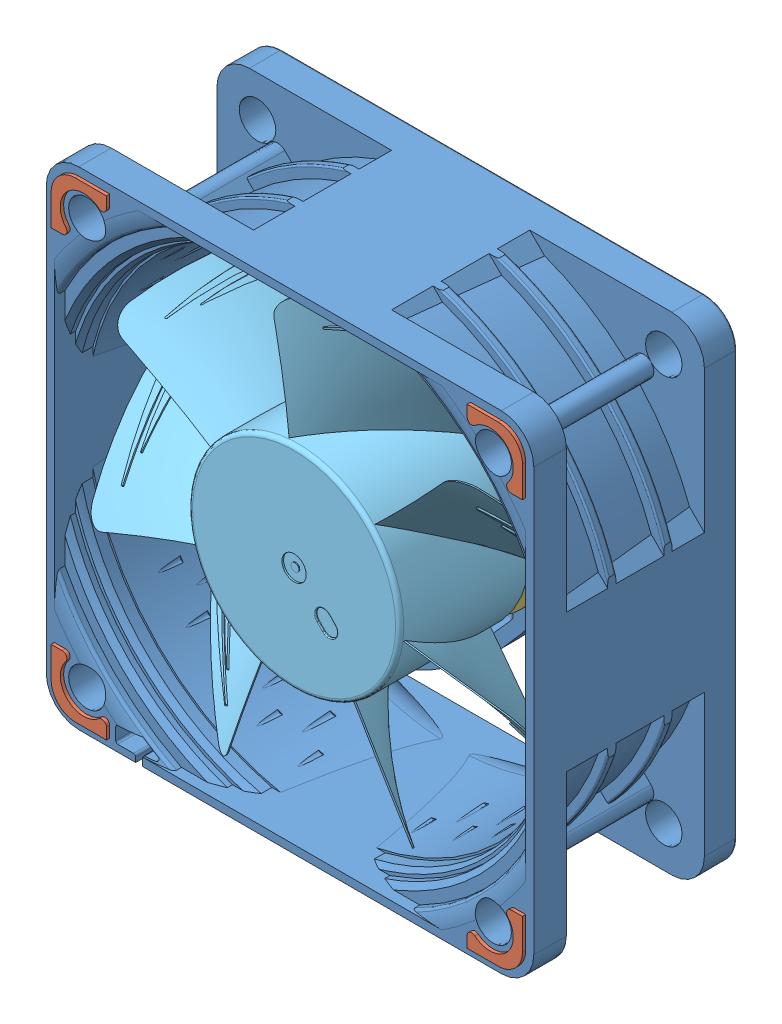
SolidWorks assembly NF-A6x25 PWM, configuration Predeterminado. Lengths in mm.
Overall size (74.25 74.23 25.8).
34 component instances, 19 part files, 30 mates.
Components (placement in the parent):
- Case A6x25-1: Case A6x25 [Predeterminado] at origin size (60 60 25.47)
- Silent block A6x25-1: Silent block A6x25 [Predeterminado] at (-25 25 24) size (6.8 6.8 1.4)
- Silent block A6x25-2: Silent block A6x25 [Predeterminado] at (25 25 24) x (0 -1 0) z (0 0 1) size (6.8 6.8 1.4)
- Silent block A6x25-7: Silent block A6x25 [Predeterminado] at (25 -25 24) x (-1 0 0) z (0 0 1) size (6.8 6.8 1.4)
- Silent block A6x25-9: Silent block A6x25 [Predeterminado] at (-25 -25 24) x (0 1 0) z (0 0 1) size (6.8 6.8 1.4)
- Silent block A6x25-11: Silent block A6x25 [Predeterminado] at (-25 25 -0.4) size (6.8 6.8 1.4)
- Silent block A6x25-6: Silent block A6x25 [Predeterminado] at (25 25 -0.4) x (0 -1 0) z (0 0 1) size (6.8 6.8 1.4)
- Silent block A6x25-8: Silent block A6x25 [Predeterminado] at (25 -25 -0.4) x (-1 0 0) z (0 0 1) size (6.8 6.8 1.4)
- Silent block A6x25-10: Silent block A6x25 [Predeterminado] at (-25 -25 -0.4) x (0 1 0) z (0 0 1) size (6.8 6.8 1.4)
- Magnet A6x25-1: Magnet A6x25 [Predeterminado] at (0 0 2) size (4.08 4.08 0.9)
- Back plate A6x25-1: Back plate A6x25 [Predeterminado] at origin size (15.2 15.2 0.4)
- Impeller A6x25-1: Impeller A6x25 [Predeterminado] at (0 0 24.5) x (0.45769 -0.889112 0) z (0 0 1) size (55.11 55.14 16.34)
- Magnetic screen A6x25-1: Magnetic screen A6x25 [Predeterminado] at (0 0 8.5) x (0.185559 -0.982633 0) z (0 0 1) size (25.6 25.6 15.6)
- Rotor A6x25-1: Rotor A6x25 [Predeterminado] at (0 0 8.5) x (-0.396278 0.91813 0) z (0 0 -1) size (25.2 25.2 15.6)
- Shaft A6x25-1: Shaft A6x25 [Predeterminado] at (0 0 24.1) x (0.396278 -0.91813 0) z (0 0 1) size (2.43 2.43 19.1)
- Oil Bearing A6x25-1: Oil Bearing A6x25 [Predeterminado] at (0 0 -5) x (1 0 0) z (0 0 -1) size (5 5 15)
  - Bearing A6x25-1: Bearing A6x25 [Predeterminado] at origin size (5 5 15)
  - Bearing gasket A6x25-1: Bearing gasket A6x25 [Predeterminado] at (0 0 -12.3) size (2 2 0.5)
  - Oil A6x25-1: Oil A6x25 [Predeterminado] at (0 0 -12.8) size (4 4 11.7)
  - Bearing gasket A6x25-2: Bearing gasket A6x25 [Predeterminado] at (0 0 -24.5) size (2 2 0.5)
- Brushless motor A6x25-1: Brushless motor A6x25 [Predeterminado] at (0 0 5) size (26 26 8.48)
  - Board A6x25-1: Board A6x25 [Predeterminado] at origin size (26 26 0.8)
  - Stator A6x25-1: Stator A6x25 [Predeterminado] at (0 0 3.55) size (11.93 12 5.5)
  - Hall Effect sensor A6x25-1: Hall Effect sensor A6x25 [WE] at (-5.3023 -0.9391 0) x (-0.233503 0.972356 0) z (-0.972356 -0.233503 0) size (6.3 1.6 2.6)
  - Controller A6x25-1: Controller A6x25 [Predeterminado] at (5.1574 2.3195 0) x (0.319288 -0.947658 0) z (0.947658 0.319288 0) size (4.81 0.99 3)
  - Coil A6x25-1: Coil A6x25 [Predeterminado] at (0 -5.01 1.29) x (-1 0 0) z (0 1 0) size (2.38 5.38 1.58)
  - Coil A6x25-2: Coil A6x25 [Predeterminado] at (-4.3388 -2.505 1.29) x (-0.5 0.866025 0) z (0.866025 0.5 0) size (2.38 5.38 1.58)
  - Coil A6x25-3: Coil A6x25 [Predeterminado] at (-4.3388 2.505 1.29) x (0.5 0.866025 0) z (0.866025 -0.5 0) size (2.38 5.38 1.58)
  - Coil A6x25-4: Coil A6x25 [Predeterminado] at (0 5.01 1.29) x (1 0 0) z (0 -1 0) size (2.38 5.38 1.58)
  - Coil A6x25-5: Coil A6x25 [Predeterminado] at (4.3388 2.505 1.29) x (0.5 -0.866025 0) z (-0.866025 -0.5 0) size (2.38 5.38 1.58)
  - Coil A6x25-6: Coil A6x25 [Predeterminado] at (4.3388 -2.505 1.29) x (-0.5 -0.866025 0) z (-0.866025 0.5 0) size (2.38 5.38 1.58)
  - Pieza2^Brushless motor A6x25-1: Pieza2^Brushless motor A6x25 [Predeterminado] at origin size (10.72 12.51 6.88) (virtual)
  - Pieza3^Brushless motor A6x25-1: Pieza3^Brushless motor A6x25 [Predeterminado] at (0 0 0.8) size (4.1 0.74 1.7) (virtual)
- Wires^NF-A6x25 PWM-1: Wires^NF-A6x25 PWM [Predeterminado] at (0 0 5) x (-1 0 0) z (0 0 -1) size (13.5 12.74 7.88) (virtual)
Mates (geometry in assembly coordinates):
- Coincidente1: coincident aligned: plane of Case-1 through (0 0 0) normal (0 0 1)
- Coincidente2: coincident aligned: plane of Case-1 through (0 0 0) normal (0 1 0)
- Coincidente3: coincident aligned: plane of Case-1 through (0 0 0) normal (1 0 0)
- Concéntrica3: concentric aligned: cylinder of Magnet A6x25-1 through (0 0 2.9) axis (0 0 -1) radius 2.04; cylinder of Back plate A6x25-1 through (0 0 0.4) axis (0 0 -1) radius 7.6
- Coincidente7: coincident anti-aligned: plane of Case-1 through (0 0 0.4) normal (0 0 -1); plane of Back plate A6x25-1 through (0 0 0.4) normal (0 0 1)
- Coincidente8: coincident aligned: plane of Magnet A6x25-1 through (0 0 2) normal (0 1 0)
- Coincidente9: coincident aligned: plane of Back plate A6x25-1 through (0 0 0) normal (0 1 0)
- Concéntrica4: concentric anti-aligned: cone of Case-1 through (0 0 0) axis (0 0 -1); cylinder of Impeller A6x25-1 through (0 0 24.5) axis (0 0 1) radius 13
- Concéntrica5: concentric anti-aligned: cylinder of Impeller A6x25-1 through (0 0 24.5) axis (0 0 1) radius 12.8; cylinder of Magnetic screen A6x25-1 through (0 0 60.3039) axis (0 0 -1) radius 12.8
- Coincidente10: coincident aligned: plane of Impeller A6x25-1 through (5.95 -11.5585 8.5) normal (0 0 -1); plane of Magnetic screen A6x25-1 through (0 0 8.5) normal (0 0 -1)
- Concéntrica6: concentric aligned: cylinder of Gasket-1 through (0 0 60.3039) axis (0 0 -1) radius 12.6; cylinder of Rotor A6x25-1 through (0 0 59.7382) axis (0 0 -1) radius 12.6
- Coincidente11: coincident aligned: plane of Gasket-1 through (0 0 8.5) normal (0 0 -1); plane of Rotor A6x25-1 through (0 0 8.5) normal (0 0 -1)
- Concéntrica7: concentric aligned: cylinder of Impeller A6x25-1 through (0 0 24.1) axis (0 0 1) radius 1; cylinder of Shaft A6x25-1 through (0 0 2.1716) axis (0 0 1) radius 1
- Coincidente12: coincident anti-aligned: plane of Impeller A6x25-1 through (0 0 24.1) normal (0 0 -1); plane of Shaft A6x25-1 through (0 0 24.1) normal (0 0 1)
- Concéntrica9: concentric aligned: cylinder of Oil Bearing A6x25-1/Bearing A6x25-1 through (0 0 -5) axis (0 0 -1) radius 2.5; cylinder of Brushless motor A6x25-1/Stator A6x25-1 through (0 0 11.3) axis (0 0 -1) radius 2.5
- EnPosición1: in place: plane of Magnet A6x25-1 through (0 0 2) normal (0 0 -1); plane of ? through (0 0 2) normal (0 0 -1); moOrthogonalPlaneRef_w of Magnet A6x25-1 through (0 0 2) normal (0 0 -1); plane of ? through (0 0 2) normal (0 1 0); plane of Magnet A6x25-1 through (0 0 2) normal (0 0 -1); plane of ? through (0 0 2) normal (-1 0 0); plane of ? through (0 0 5) normal (0 0 -1); unknown of Wires^NF-A6x25 PWM-1
- Coincidente16: coincident aligned: plane of Brushless motor A6x25-1/Board A6x25-1; plane of Wires^NF-A6x25 PWM-1
- Coincidente17: coincident aligned: moOrthogonalPlaneRef_w of Brushless motor A6x25-1/Board A6x25-1 through (0 0 5) normal (0 1 0); plane of Wires^NF-A6x25 PWM-1 through (0 0 5) normal (0 1 0)
- Coincidente18: coincident anti-aligned: moOrthogonalPlaneRef_w of Brushless motor A6x25-1/Board A6x25-1 through (0 0 5) normal (1 0 0); plane of Wires^NF-A6x25 PWM-1 through (0 0 5) normal (-1 0 0)
- Distance1: distance = 0.5 mm aligned: plane of Impeller A6x25-1 through (0 0 24.5) normal (0 0 1); plane of Case A6x25-1 through (0 0 25) normal (0 0 1)
- Concentric2: concentric anti-aligned: cylinder of Case A6x25-1 through (-25 25 24) axis (0 0 1) radius 2.875; cylinder of Silent block A6x25-1 through (-25 25 25.4) axis (0 0 -1) radius 2.875
- Coincident1: coincident anti-aligned: plane of Case A6x25-1 through (0 0 24) normal (0 0 1); plane of Silent block A6x25-1 through (-27.6287 22.7713 24) normal (0 0 -1)
- Parallel1: parallel anti-aligned: plane of Case A6x25-1 through (-22.2 0 24) normal (-1 0 0); plane of Silent block A6x25-1 through (-22.2 29 25.4) normal (1 0 0)
- Concentric3: concentric aligned: cylinder of Case A6x25-1 through (0 0 3) axis (0 0 -1) radius 13; cylinder of Brushless motor A6x25-1/Board A6x25-1 through (0 0 5.8) axis (0 0 -1) radius 13
- Coincident2: coincident anti-aligned: plane of Case A6x25-1 through (0 0 5) normal (0 0 1); plane of Brushless motor A6x25-1/Board A6x25-1 through (0 0 5) normal (0 0 -1)
- Coincident4: coincident aligned: plane of Brushless motor A6x25-1 through (0 0 5) normal (1 0 0)
- Concentric4: concentric aligned: cylinder of Case A6x25-1 through (0 0 0.4) axis (0 0 -1) radius 10; cylinder of Back plate A6x25-1 through (0 0 0.4) axis (0 0 -1) radius 7.6
- Coincident5: coincident anti-aligned: plane of Case A6x25-1 through (0 0 2) normal (0 0 1); plane of Magnet A6x25-1 through (0 0 2) normal (0 0 -1)
- Coincident6: coincident anti-aligned: plane of Oil Bearing A6x25-1 through (0 0 -5) normal (0 -1 0)
- Coincident7: coincident aligned: plane of Oil Bearing A6x25-1/Bearing A6x25-1 through (-1.5 0 5) normal (0 0 -1); plane of Brushless motor A6x25-1/Board A6x25-1 through (0 0 5) normal (0 0 -1)
